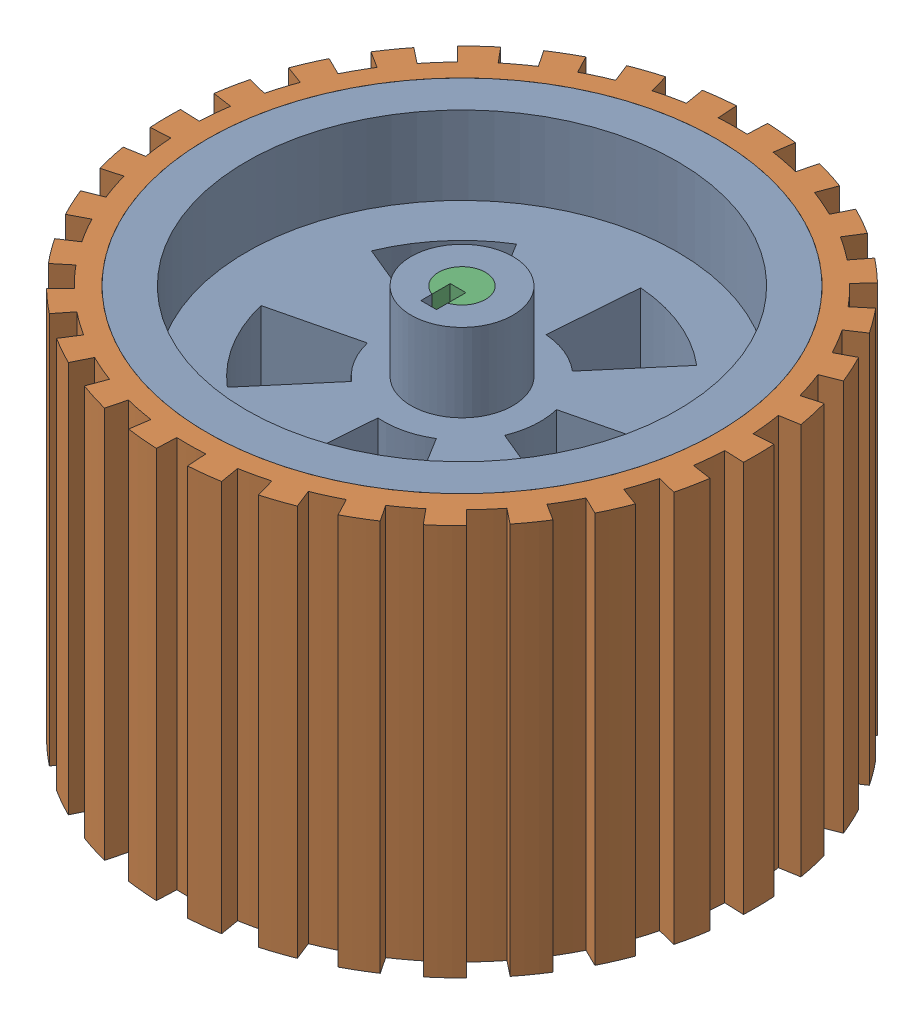
SolidWorks assembly Mirrorsupport wheel with block flange 100mm assembly, configuration Default. Lengths in mm.
Overall size (211.82 140 211.83).
5 component instances, 4 part files, 4 mates.
Components (placement in the parent):
- Mirrorside wheel (rubber+rim)-1: Mirrorside wheel (rubber+rim) [Default] at (69.3134 97.8604 -176.3592) size (211.82 100 211.83)
  - Mirrorside wheel rim-1: Mirrorside wheel rim [Default] at (68.1365 40.0161 -108.3416) size (130 100 130)
  - Mirrorside wheel rubber-1: Mirrorside wheel rubber [Default] at (68.1365 40.0161 -108.3416) x (0.734903 0 -0.678172) z (0.678172 0 0.734903) size (149.8 100 150)
- Mirrorsupport wheel shaft 100mm-1: Mirrorsupport wheel shaft 100mm [Default] at (137.4499 201.8764 -284.7008) x (1 0 0) z (0 0 -1) size (12 140 12)
- MirrorKFL001 block flange ball bearing 12 diameter shaft-1: MirrorKFL001 block flange ball bearing 12 diameter shaft [Default] at (137.4499 119.8764 -284.7008) x (-0.969898 0 -0.243511) z (-0.243511 0 0.969898) size (38 16 63)
Mates (geometry in assembly coordinates):
- Coincident1: coincident anti-aligned: circle of Mirrorside wheel (rubber+rim)-1/Mirrorside wheel rim-1; circle of Mirrorsupport wheel shaft 100mm-1
- Coincident2: coincident aligned: line of Mirrorside wheel (rubber+rim)-1/Mirrorside wheel rim-1 through (139.4499 237.8764 -279.044) axis (0 0 1); line of Mirrorsupport wheel shaft 100mm-1 through (139.4499 237.8764 -283.7008) axis (0 0 1)
- Concentric1: concentric aligned: circle of Mirrorsupport wheel shaft 100mm-1; circle of MirrorKFL001 block flange ball bearing 12 diameter shaft-1
- Distance1: distance = 18 mm anti-aligned: plane of Mirrorside wheel (rubber+rim)-1/Mirrorside wheel rim-1 through (137.4499 137.8764 -284.7008) normal (0 -1 0); plane of MirrorKFL001 block flange ball bearing 12 diameter shaft-1 through (137.4499 119.8764 -284.7008) normal (0 1 0)
